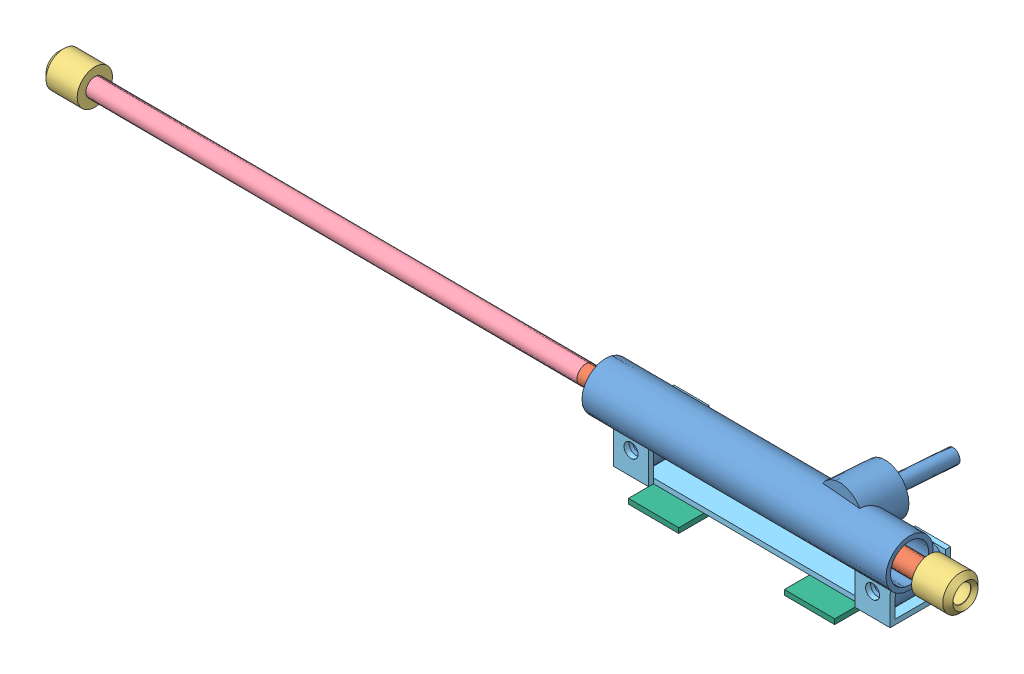
SolidWorks assembly 01071000-1-00 umiejscowienie, configuration Domyślna. Lengths in mm.
Overall size (901.58 105.1 129.05).
9 component instances, 6 part files, 1 mates.
Components (placement in the parent):
- 01072000-1-00 złożenie maglownicy-1: 01072000-1-00 złożenie maglownicy [Domyślna] at (284.0252 93.4501 -255.2746) x (-0.999982 0.005937 0) z (0 0 -1) size (901 99.75 129.05)
  - 01072000-1-01 korpus maglownicy-1: 01072000-1-01 korpus maglownicy [Domyślna] at (-110.9095 11.3781 -40.2746) size (302 89.75 127.55)
  - 01072000-1-03 wał zębaty maglownicy-1: 01072000-1-03 wał zębaty maglownicy [Domyślna] at (44.5905 11.3781 -40.2746) size (351 24.13 19)
  - 01072000-1-02 nakrętka ramienia maglownicy-1: 01072000-1-02 nakrętka ramienia maglownicy [Domyślna] at (-130.4095 11.3781 -40.2746) x (-1 0 0) z (0 0 1) size (36 35 35)
  - 01072000-1-04 przedłużka maglownicy-1: 01072000-1-04 przedłużka maglownicy [Domyślna] at (210.5905 11.3781 -40.2746) size (498 18 18)
  - 01072000-1-02 nakrętka ramienia maglownicy-2: 01072000-1-02 nakrętka ramienia maglownicy [Domyślna] at (698.5905 11.3781 -40.2746) size (36 35 35)
  - 01072000-1-11 uchwyt maglownicy-1: 01072000-1-11 uchwyt maglownicy [Domyślna] at (-96.9095 -49.1219 9.7254) size (275 40 60)
  - 01072000-1-12 podkładka uchwytu maglownicy-1: 01072000-1-12 podkładka uchwytu maglownicy [Domyślna] at (-61.9095 -54.1219 34.7254) size (50 5 100)
  - 01072000-1-12 podkładka uchwytu maglownicy-2: 01072000-1-12 podkładka uchwytu maglownicy [Domyślna] at (93.0905 -54.1219 34.7254) size (50 5 100)
Mates (geometry in assembly coordinates):
- Równolegle7: parallel anti-aligned: plane of 01072000-1-00 złożenie maglownicy-1/01072000-1-11 uchwyt maglownicy-1 through (380.6711 48.7536 -265) normal (0 0 -1)
